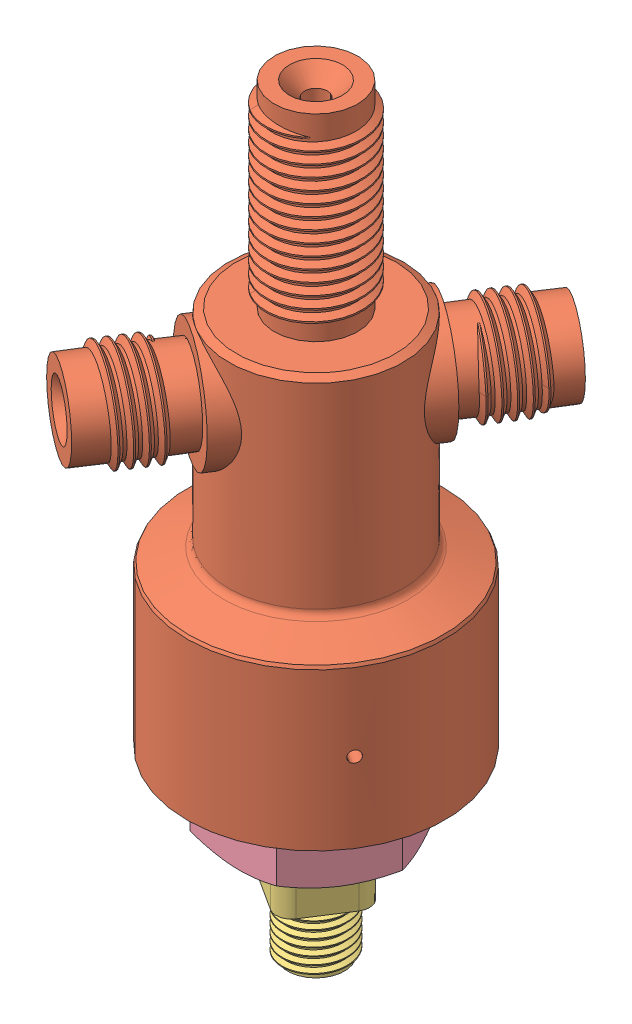
SolidWorks assembly Сборка итоговая, configuration По умолчанию. Lengths in mm.
Overall size (55.11 100.08 59.6).
6 component instances, 6 part files, 13 mates.
Components (placement in the parent):
- Болт-1: Болт [По умолчанию] at (10.5099 -7.7147 23.5) size (18 23.5 18)
- Большая штука-1: Большая штука [По умолчанию] at (10.5099 -22.2147 23.5) x (0.541276 0 -0.840845) z (0.840845 0 0.541276) size (49 76.92 34)
- Вставная штука-1: Вставная штука [По умолчанию] at (10.5099 -23.5835 23.5) x (0.840845 0 0.541276) z (0.541276 0 -0.840845) size (20 26.71 20)
- Гайка-1: Гайка [По умолчанию] at (10.5099 -7.0835 23.5) x (-0.541276 0 0.840845) z (0 -1 0) size (26.9 26.9 24.02)
- Пружина-1: Пружина [По умолчанию] at (10.5099 13.7853 23.5) x (-0.541276 0 0.840845) z (0.840845 0 0.541276) size (18.03 21.49 18.03)
- Маленькая шайба-1: Маленькая шайба [По умолчанию] at (10.5099 -9.7147 23.5) x (-0.987062 0 -0.160336) z (-0.160336 0 0.987062) size (18 10 18)
Mates (geometry in assembly coordinates):
- Концентричный1: concentric anti-aligned: circle of Вставная штука-1; cylinder of Гайка-1 through (10.5099 -23.0835 23.5) axis (0 1 0) radius 10
- Параллельность1: parallel anti-aligned: plane of Вставная штука-1 through (6.5522 -23.5991 29.6482) normal (0.840845 0 0.541276); plane of Гайка-1 through (6.5522 -23.646 29.6482) normal (-0.840845 0 -0.541276)
- Совпадение2: coincident anti-aligned: plane of Вставная штука-1 through (10.5099 -23.0835 23.5) normal (0 -1 0); plane of Гайка-1 through (10.5099 -23.0835 23.5) normal (0 1 0)
- Совпадение3: coincident anti-aligned: plane of Большая штука-1 through (10.5099 13.7853 23.5) normal (0 -1 0); plane of Пружина-1 through (10.5099 13.7853 23.5) normal (0 1 0)
- Концентричный2: concentric: cylinder of Большая штука-1 through (10.5099 13.7853 23.5) axis (0 -1 0) radius 9; point of Пружина-1
- Параллельность2: parallel: plane of Большая штука-1 through (17.0052 19.7853 13.4099) normal (0.541276 0 -0.840845); line of Пружина-1 through (17.4469 -6.2147 27.9655) axis (-0.840845 0 -0.541276)
- Концентричный5: concentric aligned: cylinder of Болт-1 through (10.5099 -7.7147 23.5) axis (0 -1 0) radius 4.5; cylinder of Большая штука-1 through (10.5099 -6.2147 23.5) axis (0 -1 0) radius 13
- Совпадение6: coincident anti-aligned: plane of Болт-1 through (6.0099 -6.2147 23.5) normal (0 1 0); plane of Пружина-1 through (10.5099 -6.2147 23.5) normal (0 -1 0)
- Совпадение7: coincident anti-aligned: plane of Болт-1 through (1.5099 -9.7147 23.5) normal (0 -1 0); plane of Маленькая шайба-1 through (14.4582 -9.7147 24.1413) normal (0 1 0)
- Концентричный6: concentric anti-aligned: cylinder of Большая штука-1 through (10.5099 -6.2147 23.5) axis (0 -1 0) radius 13; cylinder of Маленькая шайба-1 through (10.5099 1.9729 23.5) axis (0 1 0) radius 7
- Концентричный7: concentric anti-aligned: cylinder of Большая штука-1 through (10.5099 -6.2147 23.5) axis (0 -1 0) radius 13; cylinder of Гайка-1 through (10.5099 -23.0835 23.5) axis (0 1 0) radius 10
- Параллельность3: parallel anti-aligned: plane of Большая штука-1 through (3.0339 -9.7772 35.1137) normal (-0.840845 0 -0.541276); plane of Гайка-1 through (3.2313 -14.1226 34.807) normal (0.840845 0 0.541276)
- Совпадение9: coincident aligned: cone of Большая штука-1; cone of Гайка-1 through (10.5099 -7.0835 23.5) axis (0 -1 0)
